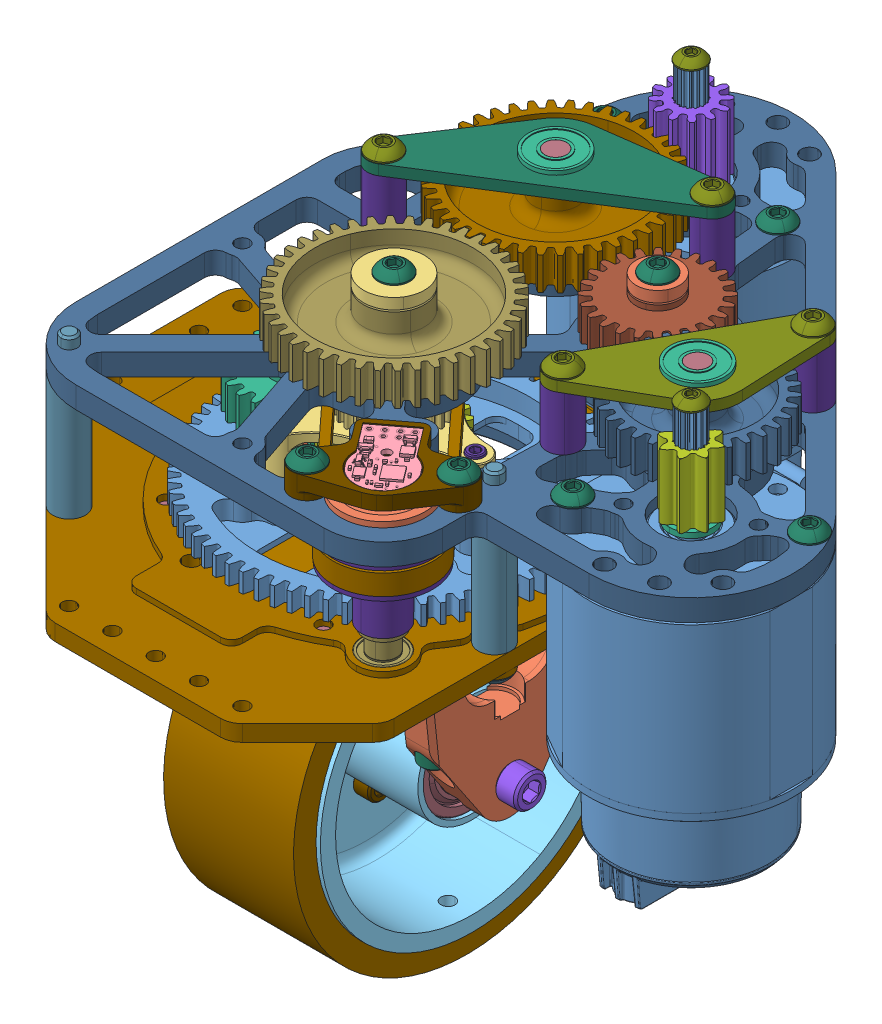
SolidWorks assembly Swerve Module, configuration Default. Lengths in mm.
Overall size (207.33 193.23 207.33).
110 component instances, 63 part files, 0 mates.
Components (placement in the parent):
- WCP-0361 - Swerve X (Tube Mount, Flipped Gears Above).step-1: WCP-0361 - Swerve X (Tube Mount, Flipped Gears Above).step [Default] at origin size (207.33 193.23 207.33)
  - WCP-0364 Rev1 - WCP X Wheel Module.step-1: WCP-0364 Rev1 - WCP X Wheel Module.step [Default] at (0 -0.825 0) size (95.62 174.54 137.74)
    - WCP-0364-001 Rev1.step-1: WCP-0364-001 Rev1.step [Default] at (0 6.35 0) size (93.93 9.53 93.93)
    - WCP-0366 Rev1_Default_As Machined_.step-1: WCP-0366 Rev1_Default_As Machined_.step [Default] at (-29.2862 -49.2125 0) x (0 0 1) z (-1 0 0) size (51.81 60.46 9.5)
    - WCP-0366 Rev1_Default_As Machined_.step-2: WCP-0366 Rev1_Default_As Machined_.step [Default] at (29.2862 -49.2125 0) x (0 0 -1) z (1 0 0) size (51.81 60.46 9.5)
    - WCP-0364-006 Rev1.step-1: WCP-0364-006 Rev1.step [Default] at (0 -49.2125 0) x (1 0 0) z (0 -0.837962 0.545729) size (56.46 12.67 12.67)
    - WCP-0364-005 Rev2.step-1: WCP-0364-005 Rev2.step [Default] at (-29.2862 -1.2827 0) x (0 -1 0) z (0 0 1) size (54.08 11 11)
    - WCP-0365 Rev2.step-1: WCP-0365 Rev2.step [Default] at (2.3061 -49.2125 0) x (0 -0.866025 -0.5) z (1 0 0) size (88.9 88.9 41.15)
    - WCP-0233 Rev1.step-1: WCP-0233 Rev1.step [Default] at (-18.0375 -49.2125 0) x (0 0 -1) z (0 1 0) size (68.52 16.32 68.56)
    - WCP-0364-002 Rev1.step-1: WCP-0364-002 Rev1.step [Default] at (0 34.5757 0) x (0 -1 0) z (0.999257 0 0.03854) size (51.69 15 15)
    - WCP-0276 Rev1.step-1: WCP-0276 Rev1.step [Default] at (-29.2862 -15.4625 0) x (0 0 1) z (1 0 0) size (25.2 12.86 25.34)
    - WCP-0364-008 Rev1.step-1: WCP-0364-008 Rev1.step [Default] at (2.3061 -49.2125 0) x (1 0 0) z (0 -0.879106 0.476626) size (38.1 101.6 101.6)
    - WCP-0357 Rev1.step-1: WCP-0357 Rev1.step [Default] at origin size (88.91 6.35 88.9)
    - WCP-0784_0375_flanged_thunderhex_bearing.step-1: WCP-0784_0375_flanged_thunderhex_bearing.step [Default] at (-29.2862 12.7 0) x (0 -1 0) z (0.06043 0 0.998172) size (7.11 24.61 24.61)
    - WCP-0775_0_250_radial_bearing.step-1: WCP-0775_0_250_radial_bearing.step [Default] at (-29.2862 -29.3687 0) x (0 -1 0) z (0.460874 0 0.887465) size (4.76 12.7 12.7)
    - WCP-0778_0_500_radial_bearing.step-1: WCP-0778_0_500_radial_bearing.step [Default] at (18.0604 -49.2125 0) x (1 0 0) z (0 -0.205758 0.978603) size (7.94 28.57 28.57)
    - WCP-0778_0_500_radial_bearing.step-2: WCP-0778_0_500_radial_bearing.step [Default] at (-17.8424 -49.2125 0) x (1 0 0) z (0 0.040496 0.99918) size (7.94 28.57 28.57)
    - WCP-0781_0_500_flanged_bearing.step-1: WCP-0781_0_500_flanged_bearing.step [Default] at (0 4.7625 0) x (0.999376 0 -0.035335) z (0.035335 0 0.999376) size (31.12 7.94 31.12)
    - NFS-0018_SHCS_#10-32_1_750L_Default_As Machined_.step-1: NFS-0018_SHCS_#10-32_1_750L_Default_As Machined_.step [Default] at (29.2862 11.1125 17.4625) x (0.988526 0 -0.151053) z (0 1 0) size (7.92 7.92 49.28)
    - NFS-0018_SHCS_#10-32_1_750L_Default_As Machined_.step-2: NFS-0018_SHCS_#10-32_1_750L_Default_As Machined_.step [Default] at (29.2862 11.1125 -17.4625) x (0.988526 0 -0.151053) z (0 1 0) size (7.92 7.92 49.28)
    - NFS-0018_SHCS_#10-32_1_750L_Default_As Machined_.step-3: NFS-0018_SHCS_#10-32_1_750L_Default_As Machined_.step [Default] at (-29.2862 11.1125 17.4625) x (0.988526 0 -0.151053) z (0 1 0) size (7.92 7.92 49.28)
    - NFS-0018_SHCS_#10-32_1_750L_Default_As Machined_.step-4: NFS-0018_SHCS_#10-32_1_750L_Default_As Machined_.step [Default] at (-29.2862 11.1125 -17.4625) x (0.988526 0 -0.151053) z (0 1 0) size (7.92 7.92 49.28)
    - 8-32 BHCS_0.500.step-1: 8-32 BHCS_0.500.step [Default] at (-29.2862 23.8633 0) x (0.940105 0 -0.340884) z (0.340884 0 0.940105) size (7.92 14.92 7.92)
    - NFS-0059_SHCS_#4-40_0_875L_91251A113.step-1: NFS-0059_SHCS_#4-40_0_875L_91251A113.step [Default] at (23.876 3.0654 0) x (0.520663 0 0.853762) z (0 -1 0) size (4.65 4.65 25.08)
    - NFS-0059_SHCS_#4-40_0_875L_91251A113.step-2: NFS-0059_SHCS_#4-40_0_875L_91251A113.step [Default] at (-11.938 3.0654 -20.6772) x (0.520663 0 0.853762) z (0 -1 0) size (4.65 4.65 25.08)
    - NFS-0059_SHCS_#4-40_0_875L_91251A113.step-3: NFS-0059_SHCS_#4-40_0_875L_91251A113.step [Default] at (-11.938 3.0654 20.6772) x (0.520663 0 0.853762) z (0 -1 0) size (4.65 4.65 25.08)
    - 10-32 SHCS - No Thread_WCP-0265 - 0.375.step-1: 10-32 SHCS - No Thread_WCP-0265 - 0.375.step [Default] at (-8.2862 -69.85 0) x (0 0.591573 -0.806252) z (0 -0.806252 -0.591573) size (7.67 14.35 7.67)
    - 10-32 SHCS - No Thread_WCP-0265 - 0.375.step-2: 10-32 SHCS - No Thread_WCP-0265 - 0.375.step [Default] at (-8.2862 -38.8937 17.8726) x (0 -0.796051 -0.60523) z (0 -0.60523 0.796051) size (7.67 14.35 7.67)
    - 10-32 SHCS - No Thread_WCP-0265 - 0.375.step-3: 10-32 SHCS - No Thread_WCP-0265 - 0.375.step [Default] at (-8.2862 -59.5312 17.8726) x (0 -0.796051 -0.60523) z (0 -0.60523 0.796051) size (7.67 14.35 7.67)
    - 10-32 SHCS - No Thread_WCP-0265 - 0.375.step-4: 10-32 SHCS - No Thread_WCP-0265 - 0.375.step [Default] at (-8.2862 -59.5312 -17.8726) x (0 -0.796051 -0.60523) z (0 -0.60523 0.796051) size (7.67 14.35 7.67)
    - 10-32 SHCS - No Thread_WCP-0265 - 0.375.step-5: 10-32 SHCS - No Thread_WCP-0265 - 0.375.step [Default] at (-8.2862 -38.8937 -17.8726) x (0 -0.796051 -0.60523) z (0 -0.60523 0.796051) size (7.67 14.35 7.67)
    - 10-32 SHCS - No Thread_WCP-0265 - 0.375.step-6: 10-32 SHCS - No Thread_WCP-0265 - 0.375.step [Default] at (-8.2862 -28.575 0) x (0 -0.796051 -0.60523) z (0 -0.60523 0.796051) size (7.67 14.35 7.67)
    - NFS-0024_250-20_thin_locknut_90566A029.step-1: NFS-0024_250-20_thin_locknut_90566A029.step [Default] at (-34.0362 -49.2125 0) x (0 0.824738 0.565516) z (0 -0.565516 0.824738) size (11.14 5.19 12.86)
    - WCP-0229 Rev1.step-1: WCP-0229 Rev1.step [Default] at (-22.6822 -49.2125 0) size (0.89 16.1 14.34)
    - WCP-0229 Rev1.step-2: WCP-0229 Rev1.step [Default] at (22.6822 -49.2125 0) size (0.89 16.1 14.34)
    - WCP-0367-002 Rev3.step-1: WCP-0367-002 Rev3.step [Default] at (0 28.6559 0) x (0 0 -1) z (1 0 0) size (49.74 26.04 44.2)
    - WCP-0367-006 Rev1.step-1: WCP-0367-006 Rev1.step [Default] at (-29.2862 -3.81 0) size (17.27 17.14 17.27)
    - WCP-0367-010 Rev1.step-1: WCP-0367-010 Rev1.step [Default] at (-29.2862 22.2758 0) x (0 0 1) z (-1 0 0) size (12.7 4.76 12.7)
    - WCP-0434 Rev1.step-1: WCP-0434 Rev1.step [Default] at (-29.2862 19 0) x (-0.327758 0 -0.944762) z (0 -1 0) size (30.3 30.48 12.6)
    - 217-5464_24T_500_hex_steel.step-1: 217-5464_24T_500_hex_steel.step [Default] at (0 19 0) x (0.428371 0 0.903603) z (0 -1 0) size (32.87 32.87 12.6)
    - NFS-0059_SHCS_#4-40_0_875L_91251A113.step-4: NFS-0059_SHCS_#4-40_0_875L_91251A113.step [Default] at (23.876 4.3561 0) x (0.431119 0 0.902295) z (0 -1 0) size (4.65 4.65 25.08)
    - NFS-0059_SHCS_#4-40_0_875L_91251A113.step-5: NFS-0059_SHCS_#4-40_0_875L_91251A113.step [Default] at (-11.938 4.3561 -20.6772) x (0.431119 0 0.902295) z (0 -1 0) size (4.65 4.65 25.08)
    - 0250-20_3L_SHCS_91251A554.step-1: 0250-20_3L_SHCS_91251A554.step [Default] at (-0.8888 -49.2125 0) x (0 -0.133483 -0.991051) z (1 0 0) size (9.53 9.53 82.55)
  - WCP-0360-001 Rev1.step-1: WCP-0360-001 Rev1.step [Default] at origin size (133.35 8 133.35)
  - WCP-0361-001 Rev2.step-1: WCP-0361-001 Rev2.step [Default] at (0 40.4813 0) size (174.12 6.35 174.12)
  - WCP-0364-003 Rev1.step-1: WCP-0364-003 Rev1.step [Default] at (38.669 7.5147 -38.669) x (0.562879 0 0.826539) z (0 1 0) size (20.01 20.32 56.54)
  - WCP-0364-004 Rev1.step-1: WCP-0364-004 Rev1.step [Default] at (36.5633 11.2839 39.7383) x (0 1 0) z (-0.373833 0 -0.927496) size (58.72 11 11)
  - WCP-0361-004 Rev1_Default_As Machined_.step-1: WCP-0361-004 Rev1_Default_As Machined_.step [Default] at (69.0125 51.9621 -19.9819) x (0 1 0) z (0.668276 0 -0.743914) size (25.16 11 11)
  - WCP-0361-004 Rev1_Default_As Machined_.step-2: WCP-0361-004 Rev1_Default_As Machined_.step [Default] at (-5.7166 51.9621 -53.1094) x (0 1 0) z (-0.852362 0 -0.522953) size (25.16 11 11)
  - WCP-0388 Rev1.step-1: WCP-0388 Rev1.step [Default] at (-47.625 19.8438 47.625) x (0 -1 0) z (0.889121 0 -0.457672) size (34.92 9.5 9.5)
  - WCP-0388 Rev1.step-2: WCP-0388 Rev1.step [Default] at (49.2125 19.8438 19.7361) x (0 -1 0) z (0.97467 0 0.223647) size (34.92 9.5 9.5)
  - WCP-0388 Rev1.step-3: WCP-0388 Rev1.step [Default] at (-19.7361 19.8438 -49.2125) x (0 -1 0) z (0.682793 0 0.730612) size (34.92 9.5 9.5)
  - WCP-0361-003 Rev1.step-1: WCP-0361-003 Rev1.step [Default] at (-5.7166 61.0312 -53.1094) x (0.846103 0 -0.533019) z (0.533019 0 0.846103) size (79.38 3 24.61)
  - WCP-0361-006 Rev1.step-1: WCP-0361-006 Rev1.step [Default] at (69.0125 61.0312 -19.9819) x (0.481501 0 -0.876446) z (0.876446 0 0.481501) size (63.5 3 24.61)
  - WCP-0203 Rev1.step-1: WCP-0203 Rev1.step [Default] at (49.7569 51.5938 0.2314) x (0 -1 0) z (-0.759691 0 -0.650284) size (15.88 9.5 9.5)
  - WCP-0203 Rev1.step-2: WCP-0203 Rev1.step [Default] at (75.7459 51.5938 -47.0747) x (0 -1 0) z (0.825334 0 0.564645) size (15.88 9.5 9.5)
  - WCP-0203 Rev1.step-3: WCP-0203 Rev1.step [Default] at (27.6413 51.5938 -65.6808) x (0 -1 0) z (-0.22935 0 -0.973344) size (15.88 9.5 9.5)
  - WCP-0203 Rev1.step-4: WCP-0203 Rev1.step [Default] at (-31.459 51.5938 -28.4494) x (0 -1 0) z (0.432553 0 -0.901608) size (15.88 9.5 9.5)
  - WCP-0307 Rev1.step-1: WCP-0307 Rev1.step [Default] at (-19.7361 -5.5913 -49.2125) x (0 -1 0) z (0.829544 0 0.558441) size (3.18 9.5 9.5)
  - 217-6515_Falcon_500_Default_As Machined_.step-1: 217-6515_Falcon_500_Default_As Machined_.step [Default] at (0.16 11.1062 -86.9695) x (0.5 0 0.866025) z (0 1 0) size (60 60 115.81)
  - 217-6515_Falcon_500_Default_As Machined_.step-2: 217-6515_Falcon_500_Default_As Machined_.step [Default] at (86.9695 11.1062 -0.16) x (0.866025 0 -0.5) z (0 1 0) size (60 60 115.81)
  - WCP-0779_0_375_flanged_bearing.step-1: WCP-0779_0_375_flanged_bearing.step [Default] at (36.5633 45.2437 39.7383) x (0 -1 0) z (0.710471 0 -0.703726) size (7.11 24.61 24.61)
  - WCP-0775_0_250_radial_bearing.step-1: WCP-0775_0_250_radial_bearing.step [Default] at (36.5633 1.6187 39.7383) x (0 1 0) z (-0.269707 0 0.962942) size (4.76 12.7 12.7)
  - WCP-0041_0_250_radial_bearing.step-1: WCP-0041_0_250_radial_bearing.step [Default] at (38.669 1.5108 -38.669) x (-0.316483 0 0.948598) z (0 -1 0) size (15.88 15.88 4.98)
  - WCP-0785_0_500_flanged_thunderhex_bearing.step-1: WCP-0785_0_500_flanged_thunderhex_bearing.step [Default] at (0 39.6875 0) x (-0.903668 0 0.428233) z (0 -1 0) size (31.12 31.12 7.94)
  - 217-2735_0_375_flanged_hex_bearing.step-1: 217-2735_0_375_flanged_hex_bearing.step [Default] at (38.669 43.6562 -38.669) x (0.628897 0 0.777488) z (0.777488 0 -0.628897) size (31.12 7.94 31.12)
  - WCP-0779_0_375_flanged_bearing.step-2: WCP-0779_0_375_flanged_bearing.step [Default] at (69.0125 45.2437 -19.9819) x (0 -1 0) z (-0.896651 0 -0.442737) size (7.11 24.61 24.61)
  - WCP-0779_0_375_flanged_bearing.step-3: WCP-0779_0_375_flanged_bearing.step [Default] at (-5.7166 45.2437 -53.1094) x (0 -1 0) z (0.589783 0 0.807562) size (7.11 24.61 24.61)
  - WCP-0042_0_250_flanged_bearing.step-1: WCP-0042_0_250_flanged_bearing.step [Default] at (69.0125 61.2077 -19.9819) x (0.808515 0 -0.588476) z (0 -1 0) size (18.24 18.24 4.98)
  - WCP-0042_0_250_flanged_bearing.step-2: WCP-0042_0_250_flanged_bearing.step [Default] at (-5.7166 61.2077 -53.1094) x (0.808515 0 -0.588476) z (0 -1 0) size (18.24 18.24 4.98)
  - 217-6915_Falcon_8T.step-1: 217-6915_Falcon_8T.step [Default] at (86.9695 53.0588 -0.16) x (0.660796 0 -0.750566) z (0 -1 0) size (13.62 13.62 19.06)
  - 217-6919_Falcon_12T.step-1: 217-6919_Falcon_12T.step [Default] at (0.16 53.0588 -86.9695) x (-0.693192 0 0.720753) z (0 1 0) size (17.78 17.78 19.05)
  - WCP-0541 Rev1.step-1: WCP-0541 Rev1.step [Default] at (-5.7166 51.5684 -53.1094) x (0.292927 0 0.956135) z (0 1 0) size (55.8 55.88 12.65)
  - WCP-0540 Rev1.step-1: WCP-0540 Rev1.step [Default] at (69.0125 51.5438 -19.9819) x (0.820194 0 -0.572086) z (0 1 0) size (43.07 43.07 12.6)
  - WCP-0538 Rev1.step-1: WCP-0538 Rev1.step [Default] at (38.669 51.5684 -38.669) x (0.37732 0 0.926083) z (0 -1 0) size (32.86 32.86 12.65)
  - WCP-0178 Rev1.step-1: WCP-0178 Rev1.step [Default] at (0 51.5684 0) x (0.927258 0 0.374423) z (0 1 0) size (55.8 55.88 12.65)
  - 10-32 BHCS - No Thread_WCP-0251 - 0.250.step-1: 10-32 BHCS - No Thread_WCP-0251 - 0.250.step [Default] at (-33.4155 -4 33.4155) x (0.140263 0 -0.990114) z (-0.990114 0 -0.140263) size (9.17 8.92 9.17)
  - 10-32 BHCS - No Thread_WCP-0259 - 2.000.step-1: 10-32 BHCS - No Thread_WCP-0259 - 2.000.step [Default] at (-47.625 -4 47.625) x (0.999892 0 -0.01471) z (-0.01471 0 -0.999892) size (9.17 53.37 9.17)
  - 10-32 BHCS - No Thread_WCP-0259 - 2.000.step-2: 10-32 BHCS - No Thread_WCP-0259 - 2.000.step [Default] at (49.2125 -4 19.7361) x (0.334009 0 -0.94257) z (-0.94257 0 -0.334009) size (9.17 53.37 9.17)
  - 10-32 BHCS - No Thread_WCP-0259 - 2.000.step-3: 10-32 BHCS - No Thread_WCP-0259 - 2.000.step [Default] at (-19.7361 -7.175 -49.2125) x (-0.998904 0 -0.046801) z (-0.046801 0 0.998904) size (9.17 53.37 9.17)
  - 10-32 BHCS - No Thread_WCP-0253 - 0.500.step-1: 10-32 BHCS - No Thread_WCP-0253 - 0.500.step [Default] at (23.914 50.2348 49.3306) x (-0.169382 0 -0.98555) z (0.98555 0 -0.169382) size (9.17 15.27 9.17)
  - 10-32 BHCS - No Thread_WCP-0253 - 0.500.step-2: 10-32 BHCS - No Thread_WCP-0253 - 0.500.step [Default] at (49.2125 50.2348 30.146) x (0.162273 0 -0.986746) z (0.986746 0 0.162273) size (9.17 15.27 9.17)
  - 8-32 BHCS_0.500.step-1: 8-32 BHCS_0.500.step [Default] at (86.9695 72.1088 -0.16) x (-0.999431 0 -0.033743) z (0.033743 0 -0.999431) size (7.92 14.92 7.92)
  - 8-32 BHCS_0.500.step-2: 8-32 BHCS_0.500.step [Default] at (0.16 72.1088 -86.9695) x (0.994914 0 -0.100726) z (0.100726 0 0.994914) size (7.92 14.92 7.92)
  - 10-32 BHCS - No Thread_WCP-0255 - 1.000.step-1: 10-32 BHCS - No Thread_WCP-0255 - 1.000.step [Default] at (-31.459 62.5312 -28.4494) x (0.932842 0 -0.360285) z (0.360285 0 0.932842) size (9.17 27.97 9.17)
  - 10-32 BHCS - No Thread_WCP-0255 - 1.000.step-2: 10-32 BHCS - No Thread_WCP-0255 - 1.000.step [Default] at (75.7459 62.5312 -47.0747) x (-0.965073 0 0.261981) z (-0.261981 0 -0.965073) size (9.17 27.97 9.17)
  - 10-32 BHCS - No Thread_WCP-0255 - 1.000.step-3: 10-32 BHCS - No Thread_WCP-0255 - 1.000.step [Default] at (49.7569 62.5312 0.2314) x (0.400913 0 0.916116) z (-0.916116 0 0.400913) size (9.17 27.97 9.17)
  - 10-32 BHCS - No Thread_WCP-0255 - 1.000.step-4: 10-32 BHCS - No Thread_WCP-0255 - 1.000.step [Default] at (27.6413 62.5312 -65.6808) x (0.279232 0 -0.960224) z (0.960224 0 0.279232) size (9.17 27.97 9.17)
  - 10-32 BHCS - No Thread_WCP-0253 - 0.500.step-3: 10-32 BHCS - No Thread_WCP-0253 - 0.500.step [Default] at (64.9724 43.6562 12.54) x (-0.441083 0 0.897466) z (-0.897466 0 -0.441083) size (9.17 15.27 9.17)
  - 10-32 BHCS - No Thread_WCP-0253 - 0.500.step-4: 10-32 BHCS - No Thread_WCP-0253 - 0.500.step [Default] at (108.9665 43.6562 -12.86) x (-0.441083 0 0.897466) z (-0.897466 0 -0.441083) size (9.17 15.27 9.17)
  - 10-32 BHCS - No Thread_WCP-0253 - 0.500.step-5: 10-32 BHCS - No Thread_WCP-0253 - 0.500.step [Default] at (-25.24 43.6562 -86.9695) x (-0.441083 0 0.897466) z (-0.897466 0 -0.441083) size (9.17 15.27 9.17)
  - 10-32 BHCS - No Thread_WCP-0253 - 0.500.step-6: 10-32 BHCS - No Thread_WCP-0253 - 0.500.step [Default] at (25.56 43.6562 -86.9695) x (-0.441083 0 0.897466) z (-0.897466 0 -0.441083) size (9.17 15.27 9.17)
  - 10-32 BHCS - No Thread_WCP-0253 - 0.500.step-7: 10-32 BHCS - No Thread_WCP-0253 - 0.500.step [Default] at (38.669 61.5691 -38.669) x (0.905057 0 -0.425291) z (0.425291 0 0.905057) size (9.17 15.27 9.17)
  - 10-32 BHCS - No Thread_WCP-0253 - 0.500.step-8: 10-32 BHCS - No Thread_WCP-0253 - 0.500.step [Default] at (0 61.5828 0) x (0.486688 0 -0.873576) z (0.873576 0 0.486688) size (9.17 15.27 9.17)
  - WCP-0367-003 Rev2.step-1: WCP-0367-003 Rev2.step [Default] at (36.5633 36.3309 39.7383) x (0.013698 0 -0.999906) z (0 1 0) size (29.05 29.05 26.83)
  - WCP-0367-012 Rev1_Straight.step-1: WCP-0367-012 Rev1_Straight.step [Default] at (36.5633 48.2156 39.7383) x (-0.796803 0 0.604239) z (-0.604239 0 -0.796803) size (41.27 6.58 26.97)
  - WCP-0367-001 Rev1.step-1: WCP-0367-001 Rev1.step [Default] at (0 35.3446 0) x (0.996516 0 -0.083401) z (0.083401 0 0.996516) size (19.05 0.51 19.05)
  - WCP-0367-014 Rev1.step-1: WCP-0367-014 Rev1.step [Default] at (38.669 58.3941 -38.669) x (0.434364 0 -0.900737) z (-0.900737 0 -0.434364) size (12.7 6.01 12.7)
  - WCP-0367-013 Rev1.step-1: WCP-0367-013 Rev1.step [Default] at (0 58.4078 0) x (-0.533005 0 0.846112) z (0.846112 0 0.533005) size (17.78 5.96 17.78)
  - 10-32 BHCS - No Thread_WCP-0251 - 0.250.step-2: 10-32 BHCS - No Thread_WCP-0251 - 0.250.step [Default] at (-42.106 -4 -21.4541) x (0.984998 0 -0.172564) z (-0.172564 0 -0.984998) size (9.17 8.92 9.17)
  - 10-32 BHCS - No Thread_WCP-0251 - 0.250.step-3: 10-32 BHCS - No Thread_WCP-0251 - 0.250.step [Default] at (7.3926 -4 -46.6749) x (0.4685 0 0.883464) z (0.883464 0 -0.4685) size (9.17 8.92 9.17)
  - 10-32 BHCS - No Thread_WCP-0251 - 0.250.step-4: 10-32 BHCS - No Thread_WCP-0251 - 0.250.step [Default] at (46.6749 -4 -7.3926) x (-0.69545 0 0.718575) z (0.718575 0 0.69545) size (9.17 8.92 9.17)
  - 10-32 BHCS - No Thread_WCP-0251 - 0.250.step-5: 10-32 BHCS - No Thread_WCP-0251 - 0.250.step [Default] at (21.4541 -4 42.106) x (-0.898311 0 -0.43936) z (-0.43936 0 0.898311) size (9.17 8.92 9.17)
  - CANcoder.step-1: CANcoder.step [Default] at (36.5426 46.4546 39.732) x (-0.796803 0 0.604239) z (0 1 0) size (15.94 23.28 4.54)
  - WCP-0156 Rev1.step-1: WCP-0156 Rev1.step [Default] at (36.5633 38.8937 39.7383) size (6.35 12.7 6.35)
  - Falcon_Motor_Spacer_0625.step-1: Falcon_Motor_Spacer_0625.step [Default] at (86.9695 42.74 -0.16) size (12.7 1.59 12.7)
  - Falcon_Motor_Spacer_0625.step-2: Falcon_Motor_Spacer_0625.step [Default] at (0.16 42.74 -86.9695) x (0.98238 0 0.186896) z (-0.186896 0 0.98238) size (12.7 1.59 12.7)
  - WCP-0787_0625L_500_hex.step-1: WCP-0787_0625L_500_hex.step [Default] at (0 44.45 0) x (0.567835 0 0.823143) z (0 -1 0) size (19.5 19.5 1.59)
  - 217-3258_0625L_375_hex.step-1: 217-3258_0625L_375_hex.step [Default] at (38.669 44.45 -38.669) x (0.988675 0 0.150072) z (0 1 0) size (15.88 15.88 1.59)
  - Encoder Belt.step-1: Encoder Belt.step [Default] at (18.2816 30.8309 19.8691) x (0.677097 0 0.735894) z (-0.735894 0 0.677097) size (83.28 6 29.28)
